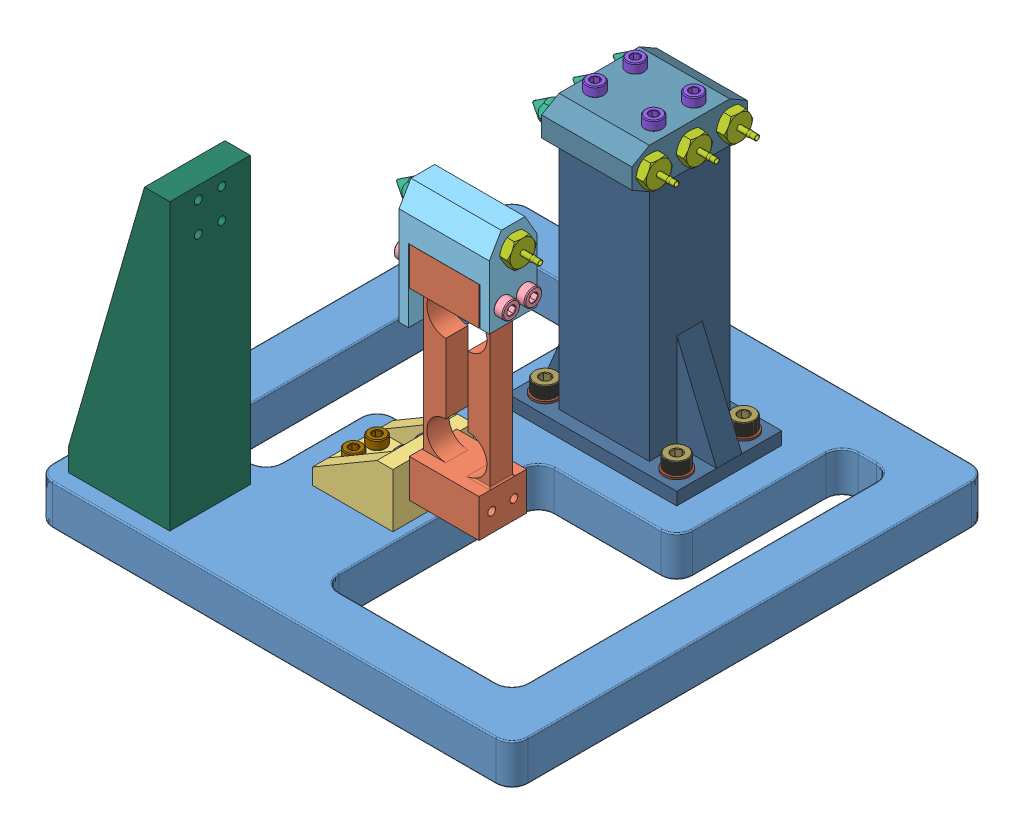
SolidWorks assembly ASSM_Prototyping Assembly, configuration Default. Lengths in mm.
Overall size (150 106.23 150).
65 component instances, 16 part files, 27 mates.
Components (placement in the parent):
- PrototypeBase-1: PrototypeBase [Default] at (-10.0282 97.0076 233.8607) size (150 12.7 150)
- SUB_Load Cell Mounting Assembly-3: SUB_Load Cell Mounting Assembly [Default] at (101.0884 104.0409 175.133) x (0 0 1) z (-1 0 0) size (25.4 101.65 59.22)
  - E05_Load Cell-1: E05_Load Cell [Default] at (-1.4723 11.6667 38.7166) x (0 1 0) z (-1 0 0) size (70 22 15)
  - M23_Load Cell Bracket-1: M23_Load Cell Bracket [Default] at (-6.6723 5.6667 64.1166) size (25.4 17 25.4)
  - M44_91292A113_18-8 Stainless Steel Socket Head Screw-1: M44_91292A113_18-8 Stainless Steel Socket Head Screw [91292A113] at (9.5277 75.6667 31.9666) x (-0.866025 -0.5 0) z (0 0 -1) size (5.5 5.5 13.21)
  - M44_91292A113_18-8 Stainless Steel Socket Head Screw-2: M44_91292A113_18-8 Stainless Steel Socket Head Screw [91292A113] at (2.5277 75.6667 31.9666) x (0.866025 -0.5 0) z (0 0 -1) size (5.5 5.5 13.21)
  - M44_91292A113_18-8 Stainless Steel Socket Head Screw-3: M44_91292A113_18-8 Stainless Steel Socket Head Screw [91292A113] at (9.5277 75.6667 23.4666) x (0.866025 -0.5 0) z (0 0 1) size (5.5 5.5 13.21)
  - M44_91292A113_18-8 Stainless Steel Socket Head Screw-4: M44_91292A113_18-8 Stainless Steel Socket Head Screw [91292A113] at (2.5277 75.6667 23.4666) x (0 -1 0) z (0 0 1) size (5.5 5.5 13.21)
  - M24_Nozzle Mount-1: M24_Nozzle Mount [Default] at (6.0277 89.7167 13.4666) size (15 37.5 28.5)
  - M20_Creality Brass Nozzle-1: M20_Creality Brass Nozzle [Default] at (6.0277 89.7167 49.9666) x (0.866025 0.5 0) z (0 0 1) size (6 7.32 13)
  - M21_5058K956_ALUMINUM LOW-PRESSURE BARBED TUBE FITTING-1: M21_5058K956_ALUMINUM LOW-PRESSURE BARBED TUBE FITTING [5058K956] at (6.0277 89.7167 12.4348) x (0 0 -1) z (0 1 0) size (15.08 9.17 7.94)
  - M41_91292A801_18-8 Stainless Steel Socket Head Screw-1: M41_91292A801_18-8 Stainless Steel Socket Head Screw [91292A801] at (2.5277 17.6667 34.2166) x (0.866025 0.5 0) z (0 0 1) size (5.5 5.5 25.38)
  - M41_91292A801_18-8 Stainless Steel Socket Head Screw-2: M41_91292A801_18-8 Stainless Steel Socket Head Screw [91292A801] at (9.5277 17.6667 34.2166) x (0.866025 0.5 0) z (0 0 1) size (5.5 5.5 25.38)
  - M25_91292A115_18-8 Stainless Steel Socket Head Screw-1: M25_91292A115_18-8 Stainless Steel Socket Head Screw [91292A115] at (2.3277 -5.3333 60.1166) x (0.866025 0 0.5) z (0 -1 0) size (5.5 5.5 19.25)
  - M25_91292A115_18-8 Stainless Steel Socket Head Screw-2: M25_91292A115_18-8 Stainless Steel Socket Head Screw [91292A115] at (9.7277 -5.3333 50.7166) x (0.866025 0 0.5) z (0 -1 0) size (5.5 5.5 19.25)
  - M25_91292A115_18-8 Stainless Steel Socket Head Screw-3: M25_91292A115_18-8 Stainless Steel Socket Head Screw [91292A115] at (9.7277 -5.3333 60.1166) x (0 0 1) z (0 -1 0) size (5.5 5.5 19.25)
  - M25_91292A115_18-8 Stainless Steel Socket Head Screw-4: M25_91292A115_18-8 Stainless Steel Socket Head Screw [91292A115] at (2.3277 -5.3333 50.7166) x (0.866025 0 0.5) z (0 -1 0) size (5.5 5.5 19.25)
- SUB_Load Cell Mounting Assembly-4: SUB_Load Cell Mounting Assembly [Default] at (21.3051 135.591 210.133) x (0 0 1) z (0 1 0) size (25.4 101.65 59.22) (hidden)
  - E05_Load Cell-1: E05_Load Cell [Default] at (-1.4723 11.6667 38.7166) x (0 1 0) z (-1 0 0) size (70 22 15)
  - M23_Load Cell Bracket-1: M23_Load Cell Bracket [Default] at (-6.6723 5.6667 64.1166) size (25.4 17 25.4)
  - M44_91292A113_18-8 Stainless Steel Socket Head Screw-1: M44_91292A113_18-8 Stainless Steel Socket Head Screw [91292A113] at (9.5277 75.6667 31.9666) x (-0.866025 -0.5 0) z (0 0 -1) size (5.5 5.5 13.21)
  - M44_91292A113_18-8 Stainless Steel Socket Head Screw-2: M44_91292A113_18-8 Stainless Steel Socket Head Screw [91292A113] at (2.5277 75.6667 31.9666) x (0.866025 -0.5 0) z (0 0 -1) size (5.5 5.5 13.21)
  - M44_91292A113_18-8 Stainless Steel Socket Head Screw-3: M44_91292A113_18-8 Stainless Steel Socket Head Screw [91292A113] at (9.5277 75.6667 23.4666) x (0.866025 -0.5 0) z (0 0 1) size (5.5 5.5 13.21)
  - M44_91292A113_18-8 Stainless Steel Socket Head Screw-4: M44_91292A113_18-8 Stainless Steel Socket Head Screw [91292A113] at (2.5277 75.6667 23.4666) x (0 -1 0) z (0 0 1) size (5.5 5.5 13.21)
  - M24_Nozzle Mount-1: M24_Nozzle Mount [Default] at (6.0277 89.7167 13.4666) size (15 37.5 28.5)
  - M20_Creality Brass Nozzle-1: M20_Creality Brass Nozzle [Default] at (6.0277 89.7167 49.9666) x (0.866025 0.5 0) z (0 0 1) size (6 7.32 13)
  - M21_5058K956_ALUMINUM LOW-PRESSURE BARBED TUBE FITTING-1: M21_5058K956_ALUMINUM LOW-PRESSURE BARBED TUBE FITTING [5058K956] at (6.0277 89.7167 12.4348) x (0 0 -1) z (0 1 0) size (15.08 9.17 7.94)
  - M41_91292A801_18-8 Stainless Steel Socket Head Screw-1: M41_91292A801_18-8 Stainless Steel Socket Head Screw [91292A801] at (2.5277 17.6667 34.2166) x (0.866025 0.5 0) z (0 0 1) size (5.5 5.5 25.38)
  - M41_91292A801_18-8 Stainless Steel Socket Head Screw-2: M41_91292A801_18-8 Stainless Steel Socket Head Screw [91292A801] at (9.5277 17.6667 34.2166) x (0.866025 0.5 0) z (0 0 1) size (5.5 5.5 25.38)
  - M25_91292A115_18-8 Stainless Steel Socket Head Screw-1: M25_91292A115_18-8 Stainless Steel Socket Head Screw [91292A115] at (2.3277 -5.3333 60.1166) x (0.866025 0 0.5) z (0 -1 0) size (5.5 5.5 19.25)
  - M25_91292A115_18-8 Stainless Steel Socket Head Screw-2: M25_91292A115_18-8 Stainless Steel Socket Head Screw [91292A115] at (9.7277 -5.3333 50.7166) x (0.866025 0 0.5) z (0 -1 0) size (5.5 5.5 19.25)
  - M25_91292A115_18-8 Stainless Steel Socket Head Screw-3: M25_91292A115_18-8 Stainless Steel Socket Head Screw [91292A115] at (9.7277 -5.3333 60.1166) x (0 0 1) z (0 -1 0) size (5.5 5.5 19.25)
  - M25_91292A115_18-8 Stainless Steel Socket Head Screw-4: M25_91292A115_18-8 Stainless Steel Socket Head Screw [91292A115] at (2.3277 -5.3333 50.7166) x (0.866025 0 0.5) z (0 -1 0) size (5.5 5.5 19.25)
- SUB_3 Nozzle Base Assmebly-1: SUB_3 Nozzle Base Assmebly [Default] at (36.7442 88.8647 144.027) x (0 0 -1) z (1 0 0) size (33.1 87.16 53.5)
  - M22b_3 Nozzle Holder-1: M22b_3 Nozzle Holder [Default] at (18.5656 24.843 36.6275) size (33.1 77.7 53.5)
  - M38_98689A113_General Purpose 18-8 Stainless Steel Washer-1: M38_98689A113_General Purpose 18-8 Stainless Steel Washer [98689A113] at (8.0156 25.443 57.3775) x (0.983948 0 -0.178454) z (0 -1 0) size (8 8 0.6)
  - M38_98689A113_General Purpose 18-8 Stainless Steel Washer-2: M38_98689A113_General Purpose 18-8 Stainless Steel Washer [98689A113] at (8.0156 25.443 15.8775) x (0.922179 0 -0.386764) z (0 -1 0) size (8 8 0.6)
  - M38_98689A113_General Purpose 18-8 Stainless Steel Washer-3: M38_98689A113_General Purpose 18-8 Stainless Steel Washer [98689A113] at (29.1156 25.443 15.8775) x (0.990958 0 -0.134172) z (0 -1 0) size (8 8 0.6)
  - M38_98689A113_General Purpose 18-8 Stainless Steel Washer-4: M38_98689A113_General Purpose 18-8 Stainless Steel Washer [98689A113] at (29.1156 25.443 57.3775) x (0.996255 0 0.086463) z (0 -1 0) size (8 8 0.6)
  - M37_90751A118_18-8 Stainless Steel Socket Head Screws-1: M37_90751A118_18-8 Stainless Steel Socket Head Screws [90751A118] at (8.0156 25.443 57.3775) x (0.866025 0 0.5) z (0 -1 0) size (7 7 18.23)
  - M37_90751A118_18-8 Stainless Steel Socket Head Screws-2: M37_90751A118_18-8 Stainless Steel Socket Head Screws [90751A118] at (8.0156 25.443 15.8775) x (0.866025 0 -0.5) z (0 -1 0) size (7 7 18.23)
  - M37_90751A118_18-8 Stainless Steel Socket Head Screws-3: M37_90751A118_18-8 Stainless Steel Socket Head Screws [90751A118] at (29.1156 25.443 15.8775) x (0.866025 0 -0.5) z (0 -1 0) size (7 7 18.23)
  - M37_90751A118_18-8 Stainless Steel Socket Head Screws-4: M37_90751A118_18-8 Stainless Steel Socket Head Screws [90751A118] at (29.1156 25.443 57.3775) x (0.866025 0 -0.5) z (0 -1 0) size (7 7 18.23)
  - M42_91828A211_18-8 Stainless Steel Hex Nut-5: M42_91828A211_18-8 Stainless Steel Hex Nut [91828A211] at (12.2156 92.343 45.8775) x (0.866025 0 -0.5) z (0 -1 0) size (5.5 6.35 2.78)
  - M42_91828A211_18-8 Stainless Steel Hex Nut-6: M42_91828A211_18-8 Stainless Steel Hex Nut [91828A211] at (24.9156 92.343 45.8775) x (0.866025 0 -0.5) z (0 -1 0) size (5.5 6.35 2.78)
  - M42_91828A211_18-8 Stainless Steel Hex Nut-7: M42_91828A211_18-8 Stainless Steel Hex Nut [91828A211] at (24.9156 92.343 27.3775) x (0.866025 0 -0.5) z (0 -1 0) size (5.5 6.35 2.78)
  - M42_91828A211_18-8 Stainless Steel Hex Nut-8: M42_91828A211_18-8 Stainless Steel Hex Nut [91828A211] at (12.2156 92.343 27.3775) x (0.866025 0 -0.5) z (0 -1 0) size (5.5 6.35 2.78)
- SUB_3 Nozzle Block Assembly-1: SUB_3 Nozzle Block Assembly [Default] at (92.0525 159.2076 114.1361) x (0 0 1) z (-1 0 0) size (36.86 25.38 45.07)
  - M22a_3 Nozzle Block-1: M22a_3 Nozzle Block [Default] at (-7.7246 28.2 32.9307) size (36.4 12.7 28.5)
  - M20_Creality Brass Nozzle-1: M20_Creality Brass Nozzle [Default] at (-1.3746 34.55 40.9307) x (0.866025 0.5 0) z (0 0 1) size (6 7.32 13)
  - M20_Creality Brass Nozzle-2: M20_Creality Brass Nozzle [Default] at (11.3254 34.55 40.9307) x (0.866025 0.5 0) z (0 0 1) size (6 7.32 13)
  - M20_Creality Brass Nozzle-3: M20_Creality Brass Nozzle [Default] at (24.0254 34.55 40.9307) x (0.866025 0.5 0) z (0 0 1) size (6 7.32 13)
  - M21_5058K956_ALUMINUM LOW-PRESSURE BARBED TUBE FITTING-1: M21_5058K956_ALUMINUM LOW-PRESSURE BARBED TUBE FITTING [5058K956] at (24.0254 34.55 3.3988) x (0 0 -1) z (0.866025 0.5 0) size (15.08 9.17 7.94)
  - M21_5058K956_ALUMINUM LOW-PRESSURE BARBED TUBE FITTING-2: M21_5058K956_ALUMINUM LOW-PRESSURE BARBED TUBE FITTING [5058K956] at (-1.3746 34.55 3.3988) x (0 0 -1) z (0.866025 0.5 0) size (15.08 9.17 7.94)
  - M21_5058K956_ALUMINUM LOW-PRESSURE BARBED TUBE FITTING-4: M21_5058K956_ALUMINUM LOW-PRESSURE BARBED TUBE FITTING [5058K956] at (11.3254 34.55 3.3988) x (0 0 -1) z (0.866025 0.5 0) size (15.08 9.17 7.94)
  - M41_91292A801_18-8 Stainless Steel Socket Head Screw-1: M41_91292A801_18-8 Stainless Steel Socket Head Screw [91292A801] at (4.9754 31.4 27.9307) x (0 0 1) z (0 1 0) size (5.5 5.5 25.38)
  - M41_91292A801_18-8 Stainless Steel Socket Head Screw-2: M41_91292A801_18-8 Stainless Steel Socket Head Screw [91292A801] at (4.9754 31.4 9.4307) x (0.866025 0 0.5) z (0 1 0) size (5.5 5.5 25.38)
  - M41_91292A801_18-8 Stainless Steel Socket Head Screw-3: M41_91292A801_18-8 Stainless Steel Socket Head Screw [91292A801] at (17.6754 31.4 27.9307) x (0 0 1) z (0 1 0) size (5.5 5.5 25.38)
  - M41_91292A801_18-8 Stainless Steel Socket Head Screw-4: M41_91292A801_18-8 Stainless Steel Socket Head Screw [91292A801] at (17.6754 31.4 9.4307) x (-0.866025 0 0.5) z (0 1 0) size (5.5 5.5 25.38)
- SUB_Calibration Stand Mounting Assembly-1: SUB_Calibration Stand Mounting Assembly [Default] at (-5.0282 109.7076 203.4607) size (32 101.12 25.4)
  - M40_Calibration Stand-1: M40_Calibration Stand [Default] at origin size (32 90 25.4)
  - M43_91292A029_18-8 Stainless Steel Socket Head Screw-1: M43_91292A029_18-8 Stainless Steel Socket Head Screw [91292A029] at (20 -11 9) x (1 0 0) z (0 -1 0) size (5.5 5.5 21.26)
  - M43_91292A029_18-8 Stainless Steel Socket Head Screw-2: M43_91292A029_18-8 Stainless Steel Socket Head Screw [91292A029] at (4 -11 9) x (1 0 0) z (0 -1 0) size (5.5 5.5 21.26)
  - M43_91292A029_18-8 Stainless Steel Socket Head Screw-3: M43_91292A029_18-8 Stainless Steel Socket Head Screw [91292A029] at (4 -11 16.4) x (1 0 0) z (0 -1 0) size (5.5 5.5 21.26)
  - M43_91292A029_18-8 Stainless Steel Socket Head Screw-4: M43_91292A029_18-8 Stainless Steel Socket Head Screw [91292A029] at (20 -11 16.4) x (1 0 0) z (0 -1 0) size (5.5 5.5 21.26)
Mates (geometry in assembly coordinates):
- Coincident22: coincident anti-aligned: plane of PrototypeBase-1 through (-10.0282 109.7076 233.8607) normal (0 1 0); plane of Air Canister Assembly-1/M28_Air Cannister Holder-2 through (387.1718 109.7076 96.1507) normal (0 -1 0)
- Distance3: distance = 8 mm aligned: plane of SUB_Air Canister Assembly-1/M28_Air Cannister Holder-2 through (387.1718 117.7076 -62.9393) normal (0 0 -1); plane of PrototypeBase-1 through (-10.0282 109.7076 83.8607) normal (0 0 -1)
- Coincident23: coincident anti-aligned: plane of PrototypeBase-1 through (-10.0282 109.7076 233.8607) normal (0 1 0); plane of SUB_Load Cell Mounting Assembly-3/M23_Load Cell Bracket-1 through (62.3718 109.7076 193.8607) normal (0 -1 0)
- Distance18: distance = 10 mm anti-aligned: plane of SUB_Load Cell Mounting Assembly-3/M23_Load Cell Bracket-1 through (36.9718 109.7076 193.8607) normal (-1 0 0); plane of SUB_Calibration Stand Mounting Assembly-1/M40_Calibration Stand-1 through (26.9718 199.7076 228.8607) normal (1 0 0)
- Distance6: distance = 40 mm aligned: plane of SUB_Load Cell Mounting Assembly-3/M23_Load Cell Bracket-1 through (36.9718 109.7076 193.8607) normal (0 0 1); plane of PrototypeBase-1 through (-10.0282 109.7076 233.8607) normal (0 0 1)
- Coincident29: coincident anti-aligned: plane of PrototypeBase-1 through (-10.0282 109.7076 233.8607) normal (0 1 0); plane of SUB_Second Stage Regulator Assembly-1/Regulator Base Fixture-1 through (35.3468 109.7076 24.2935) normal (0 -1 0)
- Coincident30: coincident anti-aligned: plane of PrototypeBase-1 through (-10.0282 109.7076 233.8607) normal (0 1 0); plane of SUB_3 Nozzle Base Assmebly-1/M22b_3 Nozzle Holder-1 through (73.3718 109.7076 125.4614) normal (0 -1 0)
- Coincident31: coincident aligned: plane of SUB_Load Cell Mounting Assembly-3/M20_Creality Brass Nozzle-1 through (64.1218 196.7576 182.8927) normal (0 1 0); plane of SUB_3 Nozzle Block Assembly-1/M20_Creality Brass Nozzle-2 through (64.1218 196.7576 127.1935) normal (0 1 0)
- Coincident32: coincident aligned: plane of SUB_Load Cell Mounting Assembly-3/M24_Nozzle Mount-1 through (59.1218 193.7576 181.1607) normal (-1 0 0); plane of SUB_3 Nozzle Block Assembly-1/M22a_3 Nozzle Block-1 through (59.1218 187.4076 106.4114) normal (-1 0 0)
- Concentric5: concentric aligned: cylinder of SUB_3 Nozzle Base Assmebly-1/M22b_3 Nozzle Holder-1 through (64.1218 175.4076 119.1114) axis (0 1 0) radius 1.7; cylinder of SUB_3 Nozzle Block Assembly-1/M22a_3 Nozzle Block-1 through (64.1218 187.4076 119.1114) axis (0 1 0) radius 1.55
- Concentric6: concentric aligned: cylinder of SUB_3 Nozzle Base Assmebly-1/M22b_3 Nozzle Holder-1 through (82.6218 175.4076 131.8114) axis (0 1 0) radius 1.7; cylinder of SUB_3 Nozzle Block Assembly-1/M22a_3 Nozzle Block-1 through (82.6218 187.4076 131.8114) axis (0 1 0) radius 1.55
- Distance11: distance = 30 mm anti-aligned: plane of SUB_3 Nozzle Block Assembly-1/M22a_3 Nozzle Block-1 through (87.6218 187.4076 143.6607) normal (0 0 1); plane of SUB_Load Cell Mounting Assembly-3/M24_Nozzle Mount-1 through (59.1218 193.7576 173.6607) normal (0 0 -1)
- Coincident33: coincident anti-aligned: plane of PrototypeBase-1 through (-10.0282 109.7076 233.8607) normal (0 1 0); plane of SUB_Calibration Stand Mounting Assembly-1/M40_Calibration Stand-1 through (26.9718 109.7076 228.8607) normal (0 -1 0)
- Distance12: distance = 5 mm aligned: plane of SUB_Calibration Stand Mounting Assembly-1/M40_Calibration Stand-1 through (-5.0282 109.7076 228.8607) normal (-1 0 0); plane of PrototypeBase-1 through (-10.0282 109.7076 233.8607) normal (-1 0 0)
- Coincident36: coincident anti-aligned: plane of SUB_Load Cell Mounting Assembly-4/M23_Load Cell Bracket-1 through (26.9718 174.3076 228.8607) normal (-1 0 0); plane of SUB_Calibration Stand Mounting Assembly-1/M40_Calibration Stand-1 through (26.9718 199.7076 228.8607) normal (1 0 0)
- Concentric7: concentric aligned: cylinder of SUB_Load Cell Mounting Assembly-4/M23_Load Cell Bracket-1 through (26.9708 195.7076 219.8607) axis (1 0 0) radius 1.55; cylinder of SUB_Calibration Stand Mounting Assembly-1/M40_Calibration Stand-1 through (26.9718 195.7076 219.8607) axis (1 0 0) radius 1.25
- Concentric8: concentric aligned: cylinder of SUB_Load Cell Mounting Assembly-4/M23_Load Cell Bracket-1 through (26.9708 186.3076 212.4607) axis (1 0 0) radius 1.55; cylinder of SUB_Calibration Stand Mounting Assembly-1/M40_Calibration Stand-1 through (26.9718 186.3076 212.4607) axis (1 0 0) radius 1.25
- Distance14: distance = 95 mm anti-aligned: plane of SUB_Solenoid Assembly-1/M01_manifold_e10m-04-1 through (182.6218 125.4576 165.4607) normal (-1 0 0); plane of SUB_Load Cell Mounting Assembly-3/M24_Nozzle Mount-1 through (87.6218 193.7576 181.1607) normal (1 0 0)
- Distance22: distance = 60 mm aligned: plane of SUB_Air Canister Assembly-1/M28_Air Cannister Holder-2 through (387.1718 173.2526 16.6057) normal (1 0 0); plane of PrototypeBase-1 through (139.9718 109.7076 233.8607) normal (1 0 0)
- Coincident42: coincident anti-aligned: plane of PrototypeBase-1 through (-10.0282 109.7076 233.8607) normal (0 1 0); plane of SUB_Solenoid Assembly-1/M01_manifold_e10m-04-1 through (195.5468 109.7076 165.4607) normal (0 -1 0)
- Distance24: distance = 25.4 mm aligned: plane of SUB_Second Stage Regulator Assembly-1/Regulator Base Fixture-1 through (15.3718 120.7576 24.2935) normal (-1 0 0); plane of PrototypeBase-1 through (-10.0282 109.7076 233.8607) normal (-1 0 0)
- Coincident44: coincident aligned: plane of SUB_Air Canister Assembly-1/M19_5346K11_Brass Barbed Hose Fitting for Air and Water-1 through (123.0791 173.2526 -20.8593) normal (0 0 -1); plane of SUB_Second Stage Regulator Assembly-1/M18_5346K12_Brass Barbed Hose Fitting for Air and Water-1 through (35.3468 130.7576 -19.9025) normal (0 0 -1)
- Distance26: distance = 4 mm aligned: plane of PrototypeBase-1 through (-10.0282 109.7076 233.8607) normal (0 0 1); plane of ElectricalAssembly-1/ElectricalBoard_V2-1 through (281.2718 92.7371 229.8607) normal (0 0 1)
- Coincident46: coincident anti-aligned: plane of PrototypeBase-1 through (-10.0282 109.7076 233.8607) normal (0 1 0); plane of ElectricalAssembly-1/ElectricalBoard_V2-1 through (325.1226 109.7076 172.1718) normal (0 -1 0)
- Distance25: distance = 10 mm aligned: plane of ElectricalAssembly-1/PCB-1 through (437.1718 132.2776 216.4482) normal (1 0 0); plane of PrototypeBase-1 through (139.9718 109.7076 233.8607) normal (1 0 0)
- Distance27: distance = 5 mm aligned: plane of SUB_Calibration Stand Mounting Assembly-1/M40_Calibration Stand-1 through (-5.0282 109.7076 228.8607) normal (0 0 1); plane of PrototypeBase-1 through (-10.0282 109.7076 233.8607) normal (0 0 1)
- Coincident48: coincident anti-aligned: plane of SUB_Solenoid Assembly-1/M04_valve_e210a-1w012-4 through (184.3828 125.4576 181.1607) normal (0 0 1); plane of SUB_Load Cell Mounting Assembly-3/M21_5058K956_ALUMINUM LOW-PRESSURE BARBED TUBE FITTING-1 through (88.6536 193.7576 181.1607) normal (0 0 -1)
